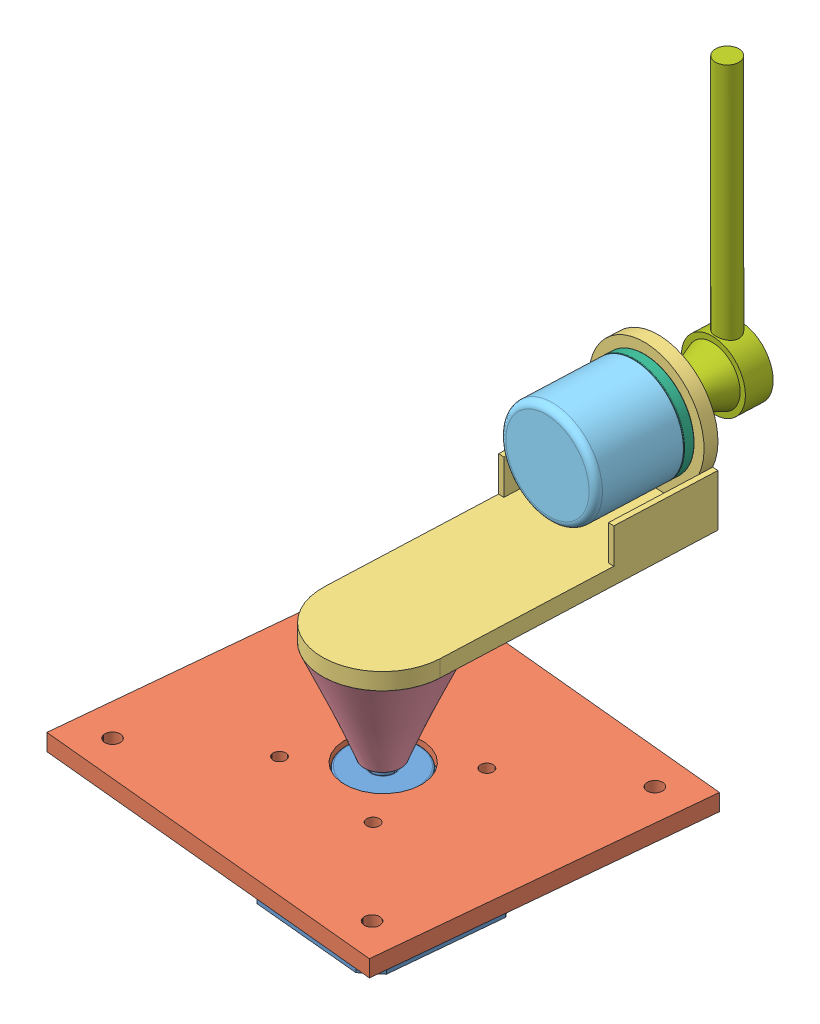
SolidWorks assembly Assem5, configuration Default. Lengths in mm.
Overall size (116.29 171.85 156.89).
11 component instances, 7 part files, 4 mates.
Components (placement in the parent):
- Top_Plate_Assembly-1: Top_Plate_Assembly [Default] at (-91.8518 -30.8738 88.0145) x (0.995303 0 0.09681) z (-0.09681 0 0.995303) size (107.5 53.2 96)
  - NEMA 17HS13-0404S1-1: NEMA 17HS13-0404S1 [Default] at (62.8961 -27.2281 30.1687) x (0.999997 0 -0.002617) z (0 1 0) size (42 42 53.2)
  - Top_Plate-2: Top_Plate [Default] at (62.8366 -29.4044 30.0281) size (107.5 5 96)
- Horizontal_Bar_Assembly-2: Horizontal_Bar_Assembly [Default] at (-115.6023 -56.4951 106.6618) x (0.040995 0 -0.999159) z (0.999159 0 0.040995) size (124.53 134.25 43.89)
  - CASE2-1: CASE2 [Default] at (65.717 38.2933 84.2435) size (98 41 36)
  - Horn-1: Horn [Default] at (-14.283 2.7933 84.2435) x (0.053314 0 -0.998578) z (0.998578 0 0.053314) size (41.83 30 39.89)
  - Rotary Encoder1-2: Rotary Encoder1 [Default] at (45.967 48.4507 82.8767) x (0 -1 0) z (-1 0 0) size (30 30 43)
    - Rotary Encoder.iam-1: Rotary Encoder.iam [Default] at origin size (30 30 43)
      - Item.ipt-1: Item.ipt [Default] at (-7.3427 1.3668 -12.75) size (30 30 25.5)
      - Silver.ipt-1: Silver.ipt [Default] at (-7.3427 1.3668 -12.75) x (1 0 0) z (0 0 -1) size (30 30 17.5)
  - Pendulum-1: Pendulum [Default] at (85.217 47.0427 83.9834) x (0 0 1) z (-1 0 0) size (20 91 19)
Mates (geometry in assembly coordinates):
- Coincident9: coincident anti-aligned: plane of Top_Plate_Assembly-1/NEMA 17HS13-0404S1-1 through (-32.1717 -38.1018 124.1305) normal (0 1 0); plane of Hbar_Assembly-2/Horn-1 through (-32.0152 -38.1018 124.3864) normal (0 -1 0)
- Coincident10: coincident anti-aligned: line of Top_Plate_Assembly-1/NEMA 17HS13-0404S1-1 through (-32.8958 -38.1018 122.0531) axis (0.995553 0 0.094206); line of Hbar_Assembly-2/Horn-1 through (-30.1316 -38.1018 122.3146) axis (-0.995553 0 -0.094206)
- Parallel4: parallel anti-aligned: plane of Top_Plate_Assembly-1/NEMA 17HS13-0404S1-1 through (-33.4767 -53.1018 121.9981) normal (0.094206 0 -0.995553); plane of Hbar_Assembly-2/Horn-1 through (-30.1316 -38.1018 122.3146) normal (-0.094206 0 0.995553)
- Coincident17: coincident anti-aligned: line of Top_Plate_Assembly-1/NEMA 17HS13-0404S1-1 through (-33.4767 -53.1018 121.9981) axis (0 1 0); line of Hbar_Assembly-2/Horn-1 through (-33.4767 -38.1018 121.9981) axis (0 -1 0)
